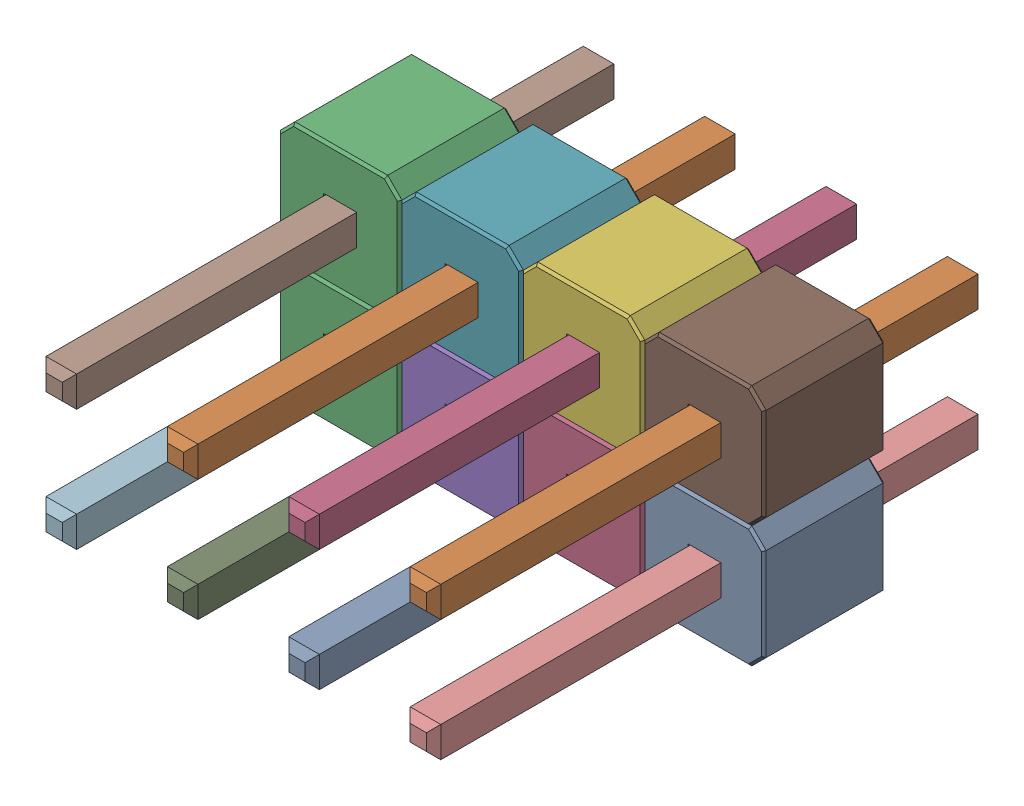
SolidWorks assembly PLD-8, configuration Default. Lengths in mm.
Overall size (10.16 5.08 11.54).
16 component instances, 2 part files, 0 mates.
Components (placement in the parent):
- _______________________-1: _______________________ [Default] at (-2.54 0 -3) size (0.64 0.64 11.54)
- _______________________-2: _______________________ [Default] at (-5.08 2.54 -3) size (0.64 0.64 11.54)
- _________-1: _________ [Default] at (-7.6724 2.5342 -0.0112) size (2.54 2.54 2.54)
- _______________________-3: _______________________ [Default] at (-2.54 2.54 -3) size (0.64 0.64 11.54)
- _________-2: _________ [Default] at (-5.1324 -0.0058 -0.0112) size (2.54 2.54 2.54)
- _________-3: _________ [Default] at (-2.5924 2.5342 -0.0112) size (2.54 2.54 2.54)
- _________-4: _________ [Default] at (-5.1324 2.5342 -0.0112) size (2.54 2.54 2.54)
- _______________________-4: _______________________ [Default] at (-7.62 2.54 -3) size (0.64 0.64 11.54)
- _______________________-5: _______________________ [Default] at (-5.08 0 -3) size (0.64 0.64 11.54)
- _______________________-6: _______________________ [Default] at (0 0 -3) size (0.64 0.64 11.54)
- _________-5: _________ [Default] at (-0.0524 2.5342 -0.0112) size (2.54 2.54 2.54)
- _______________________-7: _______________________ [Default] at (-7.62 0 -3) size (0.64 0.64 11.54)
- _________-6: _________ [Default] at (-0.0524 -0.0058 -0.0112) size (2.54 2.54 2.54)
- _______________________-8: _______________________ [Default] at (0 2.54 -3) size (0.64 0.64 11.54)
- _________-7: _________ [Default] at (-7.6724 -0.0058 -0.0112) size (2.54 2.54 2.54)
- _________-8: _________ [Default] at (-2.5924 -0.0058 -0.0112) size (2.54 2.54 2.54)
